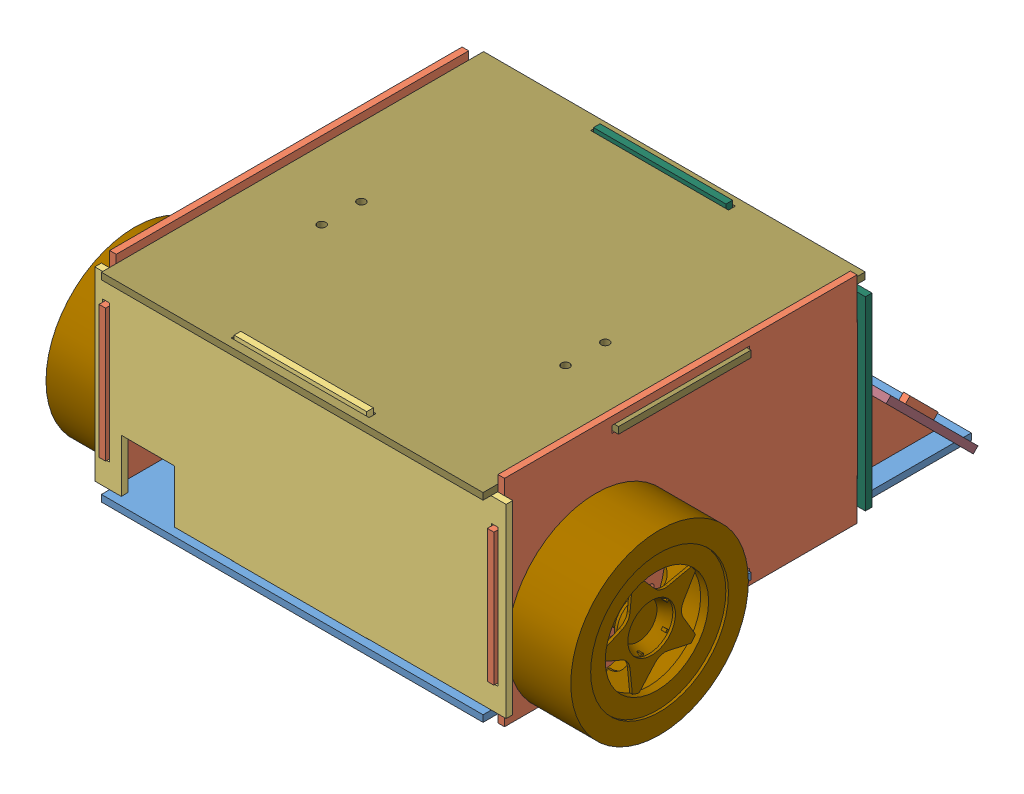
SolidWorks assembly prototype US, configuration Default. Lengths in mm.
Overall size (198 88.65 184.2).
26 component instances, 15 part files, 77 mates.
Components (placement in the parent):
- bottom-1: bottom [Default] at (69.18 75.1651 107.655) size (152 2.5 184.2)
- side-1: side [Default] at (-5.32 112.7151 107.655) x (0 -1 0) z (0 0 1) size (81.2 2.5 167.64)
- back-1: back [Default] at (69.18 112.6651 176.655) x (0 1 0) z (-1 0 0) size (78 2.5 155.2)
- side-2: side [Default] at (141.18 112.7651 107.655) x (0 -1 0) z (0 0 1) size (81.2 2.5 167.64)
- battery holder-1: battery holder [Default] at (69.18 77.6651 100.655) size (75 20 41)
- breadboard-1: breadboard [Default] at (44.0497 77.6651 60.655) size (46 9 35)
- IR sensor-1: IR sensor [Default] at (100.1989 109.1651 148.5329) x (0 0 -1) z (-1 0 0) size (35.68 17.11 13.5)
- motor driver-1: motor driver [Default] at (69.18 77.6651 145.655) size (43 26.5 43)
- IR sensor-2: IR sensor [Default] at (38.161 109.1651 148.5329) x (0 0 -1) z (-1 0 0) size (35.68 17.11 13.5)
- IR sensor-3: IR sensor [Default] at (129.0784 109.1651 62.8071) x (0 0 1) z (1 0 0) size (35.68 17.11 13.5)
- IR sensor-4: IR sensor [Default] at (9.2816 109.1651 62.8071) x (0 0 1) z (1 0 0) size (35.68 17.11 13.5)
- motor-1: motor [Default] at (16.18 98.2151 132.655) x (0 0 1) z (-1 0 0) size (67.5 22 35)
- wheel-1: wheel [Default] at (-25.82 98.2151 140.155) x (0 -1 0) z (0 0 -1) size (67 27 67)
- black disk-1: black disk [Default] at (24.18 98.2151 140.155) x (0 1 0) z (0 0 1) size (26 3 26)
- encoder-1: encoder [Default] at (23.18 114.7151 131.155) x (0 0 -1) z (-1 0 0) size (35.68 12 13.5)
- top-2: top [Default] at (69.18 147.7651 107.655) size (152 2.5 144.2)
- wheel-2: wheel [Default] at (164.18 98.2651 140.155) x (0 1 0) z (0 0 -1) size (67 27 67)
- motor-2: motor [Default] at (122.18 98.2651 132.655) x (0 0 1) z (1 0 0) size (67.5 22 35)
- black disk-2: black disk [Default] at (114.18 98.2651 140.155) x (0 -1 0) z (0 0 1) size (26 3 26)
- encoder-3: encoder [Default] at (115.18 114.7651 131.155) x (0 0 -1) z (-1 0 0) size (35.68 12 13.5)
- defender-1: defender [Default] at (69.18 94.9618 19.3517) x (1 0 0) z (0 0.707107 0.707107) size (159.2 2.5 46.5)
- ultrasonic sensor-1: ultrasonic sensor [Default] at (69.13 125.5833 43.155) x (1 0 0) z (0 1 0) size (45 12 20)
- breadboard-2: breadboard [Default] at (92.8091 77.6651 60.655) size (46 9 35)
- front2-1: front2 [Default] at (69.18 112.7151 38.605) x (1 0 0) z (0 -1 0) size (155.2 2.5 78)
- ultrasonic sensor-2: ultrasonic sensor [Default] at (22.18 125.5333 43.105) x (1 0 0) z (0 1 0) size (45 12 20)
- ultrasonic sensor-3: ultrasonic sensor [Default] at (116.18 125.5333 43.105) x (1 0 0) z (0 1 0) size (45 12 20)
Mates (geometry in assembly coordinates):
- Coincident4: coincident anti-aligned: plane of bottom-1 through (141.18 77.6651 107.655) normal (1 0 0); plane of side-2 through (141.18 112.7651 107.655) normal (-1 0 0)
- Coincident5: coincident anti-aligned: plane of bottom-1 through (69.18 75.1651 107.655) normal (0 -1 0); plane of side-2 through (143.68 75.1651 133.655) normal (0 1 0)
- Width2: width anti-aligned: plane of bottom-1 through (69.18 77.6651 132.655) normal (0 0 1); plane of side-2 through (69.18 77.6651 82.655) normal (0 0 -1); plane of bottom-1 through (143.68 87.7651 41.155) normal (0 0 -1); plane of side-2 through (143.68 72.1651 174.155) normal (0 0 1)
- Coincident15: coincident anti-aligned: plane of bottom-1 through (69.18 77.6651 107.655) normal (0 1 0); plane of motor driver-1 through (69.18 77.6651 145.655) normal (0 -1 0)
- Concentric3: concentric aligned: circle of bottom-1; circle of IR sensor-1
- Parallel3: parallel aligned: line of bottom-1 through (141.18 77.6651 132.655) axis (0 0 1); line of IR sensor-1 through (106.9489 109.1651 133.0329) axis (0 0 1)
- Distance1: distance = 30 mm anti-aligned: plane of bottom-1 through (69.18 77.6651 107.655) normal (0 1 0); plane of IR sensor-1 through (100.1989 107.6651 148.5329) normal (0 -1 0)
- Concentric4: concentric anti-aligned: circle of bottom-1; circle of IR sensor-2
- Parallel4: parallel anti-aligned: line of bottom-1 through (-2.82 77.6651 132.655) axis (0 0 1); line of IR sensor-2 through (31.411 109.1651 164.0329) axis (0 0 -1)
- Distance2: distance = 30 mm anti-aligned: plane of bottom-1 through (69.18 77.6651 107.655) normal (0 1 0); plane of IR sensor-2 through (38.161 107.6651 148.5329) normal (0 -1 0)
- Concentric5: concentric aligned: circle of bottom-1; circle of IR sensor-3
- Parallel5: parallel aligned: line of bottom-1 through (141.18 77.6651 82.655) axis (0 0 -1); line of IR sensor-3 through (122.3284 109.1651 78.3071) axis (0 0 -1)
- Distance3: distance = 30 mm anti-aligned: plane of IR sensor-3 through (129.0784 107.6651 62.8071) normal (0 -1 0); plane of bottom-1 through (69.18 77.6651 107.655) normal (0 1 0)
- Parallel6: parallel aligned: line of bottom-1 through (-2.82 77.6651 82.655) axis (0 0 -1); line of IR sensor-4 through (2.5316 109.1651 78.3071) axis (0 0 -1)
- Concentric6: concentric anti-aligned: circle of bottom-1; circle of IR sensor-4
- Distance4: distance = 30 mm anti-aligned: plane of bottom-1 through (69.18 77.6651 107.655) normal (0 1 0); plane of IR sensor-4 through (9.2816 107.6651 62.8071) normal (0 -1 0)
- Concentric7: concentric aligned: circle of bottom-1; circle of battery holder-1
- Concentric8: concentric aligned: circle of bottom-1; circle of battery holder-1
- Coincident25: coincident anti-aligned: plane of bottom-1 through (69.18 77.6651 107.655) normal (0 1 0); plane of battery holder-1 through (69.18 77.6651 100.655) normal (0 -1 0)
- Coincident26: coincident anti-aligned: plane of bottom-1 through (69.18 77.6651 107.655) normal (0 1 0); plane of breadboard-1 through (44.0497 77.6651 60.655) normal (0 -1 0)
- Parallel7: parallel aligned: line of bottom-1 through (141.18 77.6651 82.655) axis (0 0 -1); line of breadboard-1 through (67.0497 86.6651 78.155) axis (0 0 -1)
- Coincident30: coincident anti-aligned: plane of motor-1 through (-2.82 92.2151 146.155) normal (-1 0 0); plane of wheel-1 through (-2.82 98.2151 140.155) normal (1 0 0)
- Concentric9: concentric anti-aligned: circle of motor-1; circle of wheel-1
- Coincident31: coincident anti-aligned: plane of side-1 through (-2.82 112.7151 107.655) normal (1 0 0); plane of motor-1 through (-2.82 92.2151 146.155) normal (-1 0 0)
- Coincident36: coincident aligned: plane of motor-1 through (24.18 98.2151 132.655) normal (1 0 0); plane of black disk-1 through (24.18 98.2151 140.155) normal (1 0 0)
- Concentric10: concentric aligned: circle of motor-1; circle of black disk-1
- Width7: width aligned: plane of back-1 through (94.18 77.6651 174.155) normal (1 0 0); plane of bottom-1 through (44.18 77.6651 174.155) normal (-1 0 0); plane of back-1 through (43.18 77.6651 107.655) normal (1 0 0); plane of bottom-1 through (95.18 77.6651 107.655) normal (-1 0 0)
- Coincident37: coincident anti-aligned: plane of bottom-1 through (69.18 77.6651 174.155) normal (0 0 1); plane of back-1 through (69.18 112.6651 174.155) normal (0 0 -1)
- Coincident38: coincident anti-aligned: plane of bottom-1 through (69.18 77.6651 107.655) normal (0 1 0); plane of back-1 through (146.78 77.6651 174.155) normal (0 -1 0)
- Parallel9: parallel anti-aligned: line of side-1 through (-2.82 153.3151 41.155) axis (0 0 1); line of encoder-1 through (16.43 114.7151 146.655) axis (0 0 -1)
- Tangent1: tangent anti-aligned: cylinder of black disk-1 through (22.18 98.2151 140.155) axis (1 0 0) radius 13; plane of encoder-1 through (23.18 111.2151 131.155) normal (0 -1 0)
- Width8: width aligned: plane of black disk-1 through (24.18 98.2151 140.155) normal (1 0 0); plane of encoder-1 through (22.18 98.2151 140.155) normal (-1 0 0); plane of black disk-1 through (29.43 102.7151 131.155) normal (1 0 0); plane of encoder-1 through (16.93 102.7151 131.155) normal (-1 0 0)
- Parallel10: parallel anti-aligned: line of motor-1 through (24.18 100.4651 139.0653) axis (0 -1 0); line of black disk-1 through (24.18 95.9651 138.5738) axis (0 1 0)
- Width9: width anti-aligned: plane of encoder-1 through (23.18 102.7151 145.655) normal (0 0 1); plane of motor-1 through (23.18 102.7151 134.655) normal (0 0 -1); plane of encoder-1 through (24.18 98.2151 139.0653) normal (0 0 -1); plane of motor-1 through (24.18 98.2151 141.2447) normal (0 0 1)
- Parallel13: parallel aligned: line of motor-1 through (24.18 100.4651 141.2447) axis (0 -1 0); line of wheel-1 through (-2.82 100.4512 142.155) axis (0 -1 0)
- Concentric14: concentric aligned: circle of side-1; circle of wheel-1
- Concentric15: concentric aligned: circle of side-1; circle of motor-1
- Concentric16: concentric aligned: circle of side-1; circle of motor-1
- Coincident44: coincident anti-aligned: plane of bottom-1 through (-2.82 77.6651 107.655) normal (-1 0 0); plane of side-1 through (-2.82 112.7151 107.655) normal (1 0 0)
- Width10: width aligned: plane of bottom-1 through (69.18 77.6651 82.655) normal (0 0 -1); plane of bottom-1 through (69.18 77.6651 132.655) normal (0 0 1); plane of side-1 through (-2.82 137.7151 37.155) normal (0 0 -1); plane of side-1 through (-2.82 137.7151 178.155) normal (0 0 1)
- Width11: width anti-aligned: plane of side-1 through (-2.82 77.7151 133.655) normal (0 -1 0); plane of side-1 through (-2.82 75.1151 133.655) normal (0 1 0); plane of bottom-1 through (69.18 77.6651 107.655) normal (0 1 0); plane of bottom-1 through (69.18 75.1651 107.655) normal (0 -1 0)
- Width13: width anti-aligned: plane of top-2 through (69.18 150.2651 107.655) normal (0 1 0); plane of top-2 through (69.18 147.7651 107.655) normal (0 -1 0); plane of side-1 through (-2.82 150.3151 133.655) normal (0 -1 0); plane of side-1 through (-2.82 147.7151 133.655) normal (0 1 0)
- Width14: width aligned: plane of side-1 through (-2.82 150.3151 133.655) normal (0 0 -1); plane of side-1 through (-2.82 150.3151 81.655) normal (0 0 1); plane of top-2 through (-2.82 150.2651 82.655) normal (0 0 -1); plane of top-2 through (-6.82 150.2651 132.655) normal (0 0 1)
- Width15: width anti-aligned: plane of top-2 through (-2.82 150.2651 132.655) normal (-1 0 0); plane of top-2 through (141.18 150.2651 179.755) normal (1 0 0); plane of back-1 through (94.18 147.6651 174.155) normal (1 0 0); plane of back-1 through (44.18 147.6651 174.155) normal (-1 0 0)
- Concentric17: concentric anti-aligned: circle of wheel-2; circle of motor-2
- Coincident47: coincident anti-aligned: plane of wheel-2 through (141.18 98.2651 140.155) normal (-1 0 0); plane of motor-2 through (141.18 104.2651 146.155) normal (1 0 0)
- Parallel14: parallel anti-aligned: line of motor-2 through (114.18 96.0151 139.0653) axis (0 1 0); line of black disk-2 through (114.18 100.5151 138.5738) axis (0 -1 0)
- Concentric18: concentric aligned: circle of motor-2; circle of black disk-2
- Coincident48: coincident aligned: plane of motor-2 through (114.18 98.2651 132.655) normal (-1 0 0); plane of black disk-2 through (114.18 98.2651 140.155) normal (-1 0 0)
- Parallel15: parallel aligned: line of wheel-2 through (141.18 96.029 142.155) axis (0 1 0); line of motor-2 through (114.18 96.0151 141.2447) axis (0 1 0)
- Concentric19: concentric anti-aligned: circle of side-2; circle of wheel-2
- Coincident50: coincident anti-aligned: plane of side-2 through (141.18 112.7651 107.655) normal (-1 0 0); plane of motor-2 through (141.18 104.2651 146.155) normal (1 0 0)
- Parallel16: parallel aligned: line of side-2 through (141.18 153.3651 41.155) axis (0 0 1); line of motor-2 through (122.18 109.2651 114.155) axis (0 0 1)
- Width18: width aligned: plane of encoder-3 through (108.93 102.7651 131.155) normal (-1 0 0); plane of encoder-3 through (121.43 102.7651 131.155) normal (1 0 0); plane of black disk-2 through (114.18 98.2651 140.155) normal (-1 0 0); plane of black disk-2 through (116.18 98.2651 140.155) normal (1 0 0)
- Tangent3: tangent anti-aligned: cylinder of black disk-2 through (116.18 98.2651 140.155) axis (-1 0 0) radius 13; plane of encoder-3 through (115.18 111.2651 131.155) normal (0 -1 0)
- Width19: width aligned: plane of encoder-3 through (115.18 102.7651 134.655) normal (0 0 -1); plane of encoder-3 through (115.18 102.7651 145.655) normal (0 0 1); plane of motor-2 through (114.18 98.2651 139.0653) normal (0 0 -1); plane of motor-2 through (114.18 98.2651 141.2447) normal (0 0 1)
- Concentric20: concentric anti-aligned: circle of side-2; circle of motor-2
- Concentric21: concentric anti-aligned: circle of side-2; circle of motor-2
- Coincident52: coincident anti-aligned: plane of side-2 through (141.18 148.0151 72.405) normal (0 0.707107 -0.707107); plane of defender-1 through (69.18 94.9618 19.3517) normal (0 -0.707107 0.707107)
- Width20: width anti-aligned: plane of side-2 through (141.18 54.4085 49.2984) normal (0 -0.707107 -0.707107); plane of side-2 through (141.18 65.0151 59.905) normal (0 0.707107 0.707107); plane of defender-1 through (143.78 91.0727 11.9271) normal (0 0.707107 0.707107); plane of defender-1 through (143.78 102.3864 23.2408) normal (0 -0.707107 -0.707107)
- Coincident53: coincident anti-aligned: plane of side-2 through (141.18 112.7651 107.655) normal (-1 0 0); plane of defender-1 through (141.18 102.3864 23.2408) normal (1 0 0)
- Coincident54: coincident anti-aligned: plane of side-1 through (-2.82 112.7151 107.655) normal (1 0 0); plane of defender-1 through (-2.82 102.3864 23.2408) normal (-1 0 0)
- Coincident62: coincident anti-aligned: plane of bottom-1 through (69.18 77.6651 107.655) normal (0 1 0); plane of breadboard-2 through (92.8091 77.6651 60.655) normal (0 -1 0)
- Lock1: lock: unknown of bottom-1; unknown of breadboard-1
- Lock2: lock: unknown of bottom-1; unknown of breadboard-2
- Concentric25: concentric aligned: circle of bottom-1; circle of motor driver-1
- Concentric26: concentric aligned: circle of bottom-1; circle of motor driver-1
- Width22: width aligned: plane of front2-1 through (69.18 112.7151 38.605) normal (0 0 -1); plane of front2-1 through (69.18 112.7151 41.105) normal (0 0 1); plane of top-2 through (43.18 150.2651 41.155) normal (0 0 -1); plane of top-2 through (43.18 150.2651 38.555) normal (0 0 1)
- Width23: width anti-aligned: plane of front2-1 through (94.18 147.7151 41.105) normal (0 1 0); plane of front2-1 through (146.78 77.7151 41.105) normal (0 -1 0); plane of bottom-1 through (69.18 75.1651 107.655) normal (0 -1 0); plane of top-2 through (69.18 150.2651 107.655) normal (0 1 0)
- Coincident63: coincident anti-aligned: plane of side-2 through (141.18 112.7651 107.655) normal (-1 0 0); plane of front2-1 through (141.18 86.7151 41.105) normal (1 0 0)
- Width25: width anti-aligned: plane of side-2 through (143.68 112.7651 107.655) normal (1 0 0); plane of side-1 through (-5.32 112.7151 107.655) normal (-1 0 0); plane of front2-1 through (-8.42 147.7151 41.105) normal (-1 0 0); plane of front2-1 through (146.78 147.7151 41.105) normal (1 0 0)
- Concentric27: concentric anti-aligned: circle of front2-1; circle of ultrasonic sensor-2
- Concentric28: concentric anti-aligned: circle of front2-1; circle of ultrasonic sensor-2
- Coincident67: coincident anti-aligned: plane of front2-1 through (69.18 112.7151 41.105) normal (0 0 1); plane of ultrasonic sensor-2 through (22.18 125.5333 41.105) normal (0 0 -1)
- Concentric29: concentric anti-aligned: circle of front2-1; circle of ultrasonic sensor-3
- Concentric30: concentric aligned: circle of front2-1; cylinder of ultrasonic sensor-3 through (137.18 134.0333 41.105) axis (0 0 1) radius 1
- Coincident70: coincident anti-aligned: plane of front2-1 through (69.18 112.7151 41.105) normal (0 0 1); plane of ultrasonic sensor-3 through (116.18 125.5333 41.105) normal (0 0 -1)
